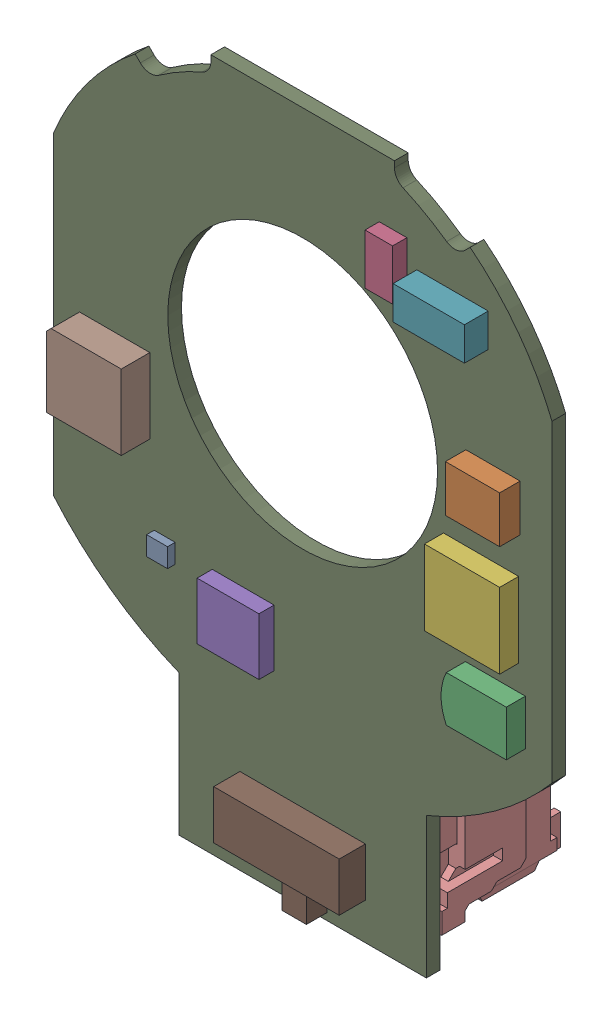
SolidWorks assembly CUI_DEVICES_amt22_asm partial(223), configuration Default. Lengths in mm.
Overall size (26.62 36.93 9.56).
11 component instances, 11 part files, 0 mates.
Components (placement in the parent):
- CUI_DEVICES_ecad_sot-963-1-1: CUI_DEVICES_ecad_sot-963-1 [Default] at origin size (1.12 1.02 0.41)
- CUI_DEVICES_ecad_sot-363-1-1: CUI_DEVICES_ecad_sot-363-1 [Default] at origin size (2.9 2.49 1.09)
- CUI_DEVICES_ecad_resonator-1-1: CUI_DEVICES_ecad_resonator-1 [Default] at origin size (3.47 2.44 1.02)
- CUI_DEVICES_ecad_cc0603c-1-1: CUI_DEVICES_ecad_cc0603c-1 [Default] at origin size (1.47 2.69 0.76)
- CUI_DEVICES_ecad_vson-8p-1-1: CUI_DEVICES_ecad_vson-8p-1 [Default] at origin size (3.3 3.04 0.81)
- CUI_DEVICES_ecad_qfn21p4x4-1-1: CUI_DEVICES_ecad_qfn21p4x4-1 [Default] at origin size (4.01 4.01 1.02)
- CUI_DEVICES_ecad_sot-23-5c-1-1: CUI_DEVICES_ecad_sot-23-5c-1 [Default] at origin size (3.81 1.78 1.27)
- CUI_DEVICES_ecad_qfn24-1-1: CUI_DEVICES_ecad_qfn24-1 [Default] at origin size (4 4 1.52)
- CUI_DEVICES_amt21r2-1-1: CUI_DEVICES_amt21r2-1 [Default] at origin size (26.62 36.93 0.73)
- CUI_DEVICES_5025840660-1-1: CUI_DEVICES_5025840660-1 [Default] at origin size (13.3 7.4 7.3)
- CUI_DEVICES_ssss810701(default)-1: CUI_DEVICES_ssss810701(default) [Default] at (50.8 30.3478 0.7315) x (1 0 0) z (0 -1 0) size (6.7 1.4 4.1)
